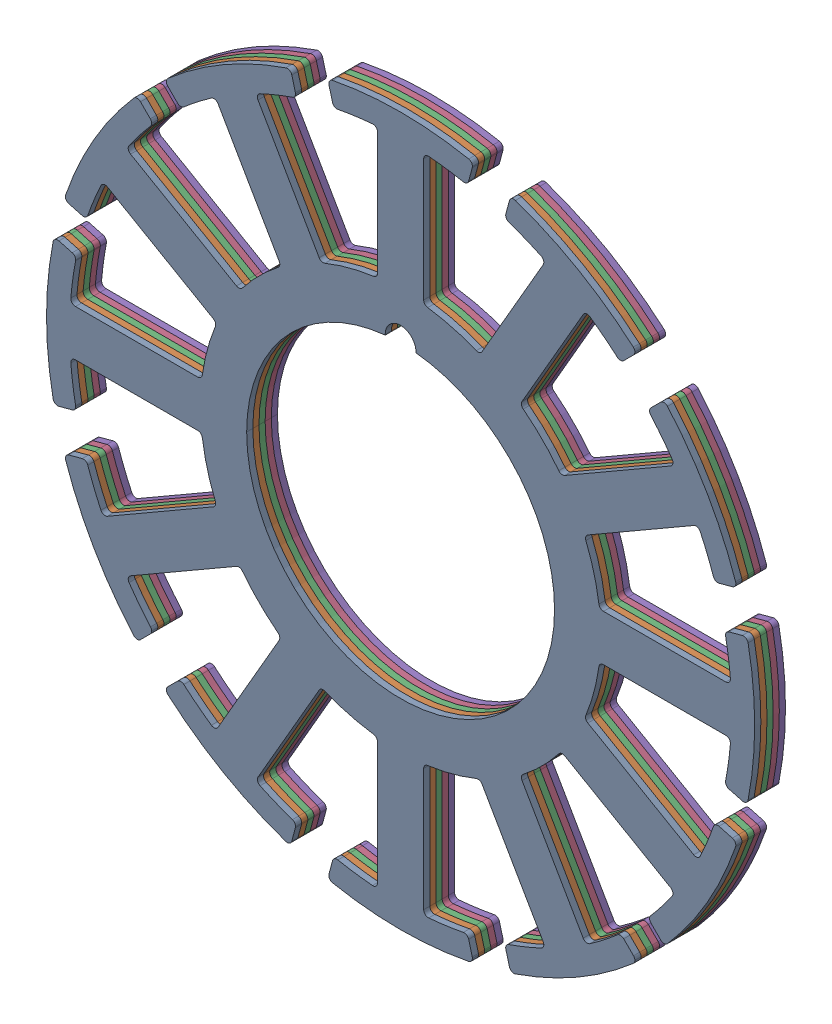
SolidWorks assembly 23x10x1mm-Stator.STEP, configuration Default. Lengths in mm.
Overall size (23 23 1).
5 component instances, 1 part files, 0 mates.
Components (placement in the parent):
- 23x10-Stator-Plate.STEP-1: 23x10-Stator-Plate.STEP [Default] at (-25.8459 0.0676 13.4926) size (23 23 0.2)
- 23x10-Stator-Plate.STEP-2: 23x10-Stator-Plate.STEP [Default] at (-25.8459 0.0676 13.2926) size (23 23 0.2)
- 23x10-Stator-Plate.STEP-3: 23x10-Stator-Plate.STEP [Default] at (-25.8459 0.0676 13.0926) size (23 23 0.2)
- 23x10-Stator-Plate.STEP-4: 23x10-Stator-Plate.STEP [Default] at (-25.8459 0.0676 12.8926) size (23 23 0.2)
- 23x10-Stator-Plate.STEP-5: 23x10-Stator-Plate.STEP [Default] at (-25.8459 0.0676 12.6926) size (23 23 0.2)
